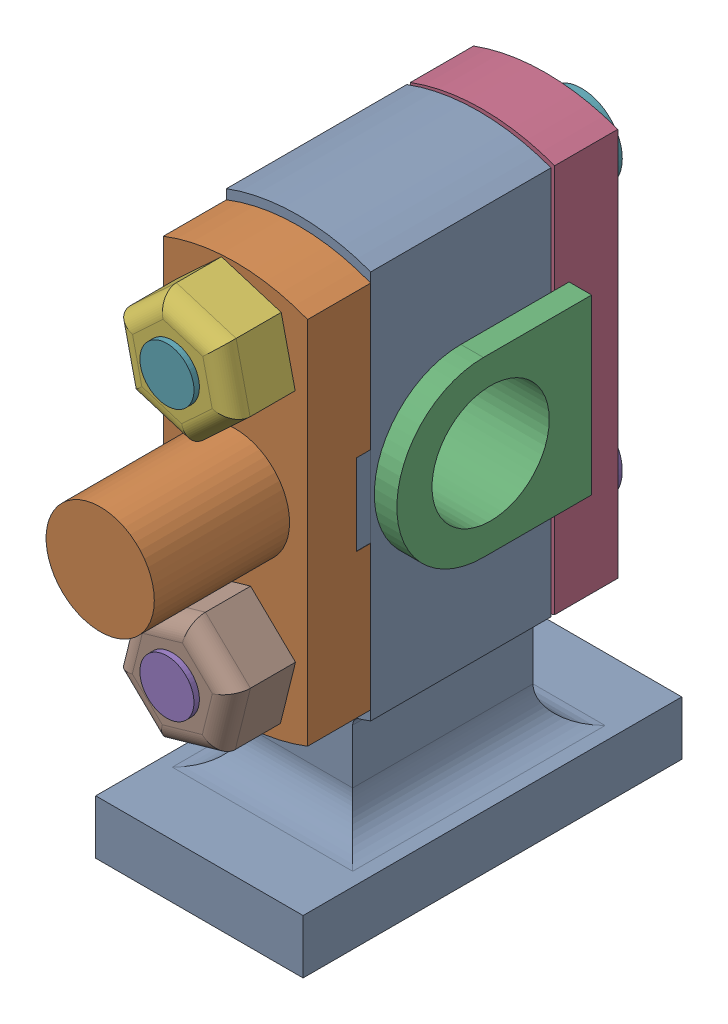
SolidWorks assembly Assem1, configuration Default. Lengths in mm.
Overall size (115 310.47 267).
8 component instances, 6 part files, 17 mates.
Components (placement in the parent):
- body-1: body [Default] at (-6.7745 49.0966 -2.6053) size (115 310 210)
- piston rod.-1: piston rod. [Default] at (190.1518 -112.4841 47.3947) size (80 220 110)
- Part2-1: Part2 [Default] at (33.2255 -48.7784 171.1873) x (0 0 1) z (-1 0 0) size (108 96 105)
- keep plate-1: keep plate [Default] at (90.5981 25.4377 -89.6053) size (80 230 35)
- bolt-1: bolt [Default] at (-45.2354 -35.2088 -109.6053) x (-0.807997 -0.589187 0) z (0 0 1) size (45 45 230)
- nut-1: nut [Default] at (-52.4181 156.0766 117.3947) x (-0.223619 0.974677 0) z (0 0 -1) size (69.28 60 35)
- bolt-2: bolt [Default] at (27.5811 104.4618 -109.6053) x (0.992004 -0.126205 0) z (0 0 1) size (45 45 230)
- nut-2: nut [Default] at (-33.0107 23.267 117.3947) x (0.24155 0.970388 0) z (0 0 -1) size (69.28 60 35)
Mates (geometry in assembly coordinates):
- Coincident1: coincident: plane of body-1 through (-6.7745 49.0966 55.3947) normal (0 0 1); plane of piston rod.-1 through (303.2255 71.5966 55.3947) normal (0 0 -1)
- Coincident2: coincident: plane of body-1 through (-6.7745 71.5966 55.3947) normal (0 1 0); plane of piston rod.-1 through (303.2255 71.5966 39.3947) normal (0 -1 0)
- Coincident3: coincident: plane of body-1 through (33.2255 49.0966 -52.6053) normal (1 0 0); plane of piston rod.-1 through (33.2255 151.5661 82.3947) normal (1 0 0)
- Concentric1: concentric: cylinder of body-1 through (91.2255 49.0966 -2.6053) axis (-1 0 0) radius 40; cylinder of Part2-1 through (-46.7745 49.0966 -2.6053) axis (1 0 0) radius 40
- Coincident4: coincident: plane of body-1 through (91.2255 89.0966 -2.6053) normal (0 -1 0); plane of Part2-1 through (-46.7745 89.0966 -54.6053) normal (0 1 0)
- Width1: width: plane of Part2-1 through (45.7255 49.0966 -2.6053) normal (1 0 0); plane of body-1 through (-59.2745 -48.7784 171.1873) normal (-1 0 0); plane of Part2-1 through (-46.7745 49.0966 -52.6053) normal (-1 0 0); plane of body-1 through (33.2255 49.0966 -52.6053) normal (1 0 0)
- Coincident5: coincident: plane of Part2-1 through (-46.7745 89.0966 -54.6053) normal (0 0 -1); plane of keep plate-1 through (-6.7745 49.0966 -54.6053) normal (0 0 1)
- Concentric2: concentric: circle of body-1; circle of keep plate-1
- Concentric3: concentric: circle of body-1; circle of keep plate-1
- Coincident9: coincident: plane of Part2-1 through (-46.7745 89.0966 -54.6053) normal (0 0 -1); plane of keep plate-1 through (-6.7745 49.0966 -54.6053) normal (0 0 1)
- Concentric4: concentric: circle of keep plate-1; circle of bolt-2
- Coincident16: coincident: plane of keep plate-1 through (-6.7745 49.0966 -89.6053) normal (0 0 -1); circle of bolt-2
- Coincident17: coincident: plane of piston rod.-1 through (-6.7745 49.0966 82.3947) normal (0 0 1); line of nut-1 through (26.339 113.9233 82.3947) axis (-0.732285 -0.680998 0)
- Concentric5: concentric: circle of nut-1; circle of bolt-2
- Coincident19: coincident: circle of piston rod.-1; circle of nut-2
- Concentric6: concentric: circle of keep plate-1; circle of bolt-1
- Coincident21: coincident: plane of keep plate-1 through (-6.7745 49.0966 -89.6053) normal (0 0 -1); circle of bolt-1
